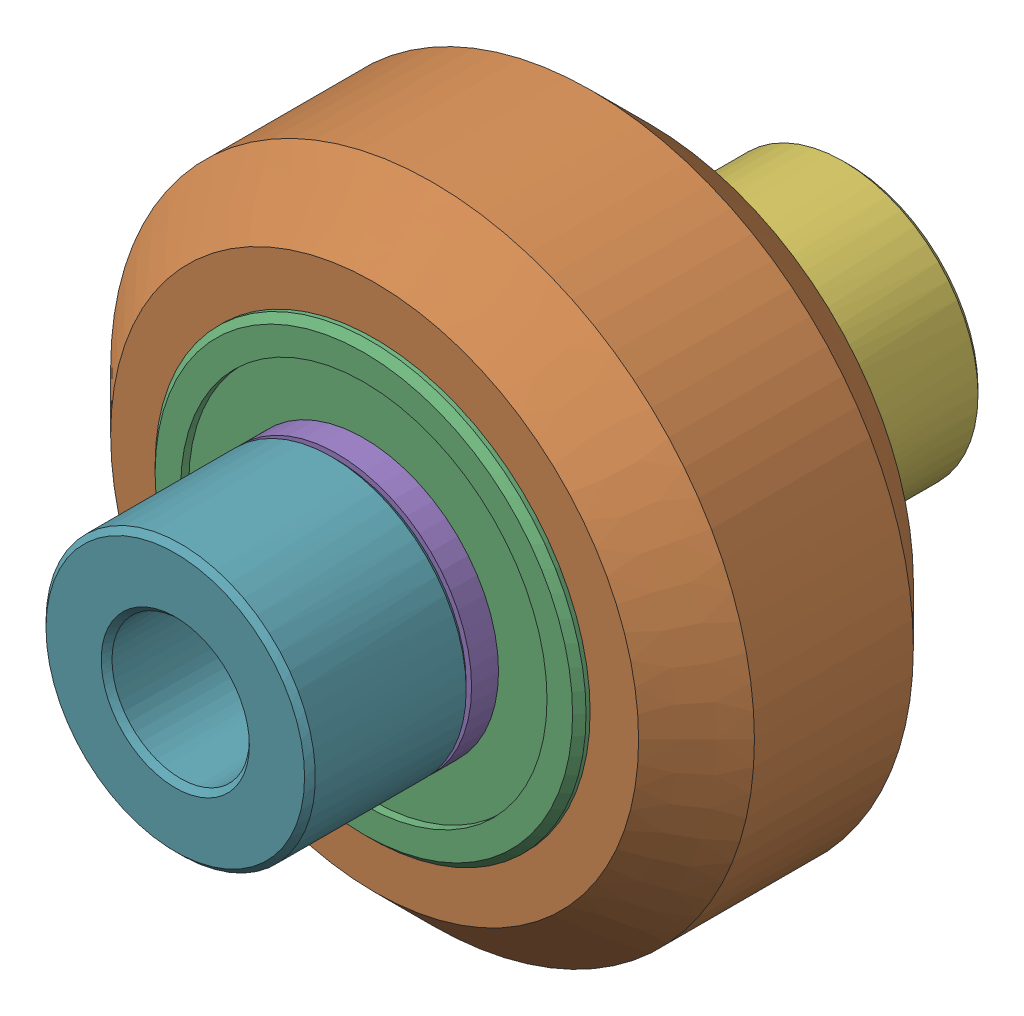
SolidWorks assembly Inboard Wheel Stack_1, configuration Default. Lengths in mm.
Overall size (23.9 23.9 25).
9 component instances, 4 part files, 0 mates.
Components (placement in the parent):
- Xtreme Solid V Wheel Kit Assembly_1-1: Xtreme Solid V Wheel Kit Assembly_1 [Default] at origin size (23.9 23.9 13)
  - Precision Shim - 10x5x1mm-1: Precision Shim - 10x5x1mm [Default] at origin size (10 10 1)
  - Xtreme Solid V Wheel Assembly_1-1: Xtreme Solid V Wheel Assembly_1 [Default] at (45.15 55 -23.5) size (23.9 23.9 11)
    - Xtreme Solid V Wheel-1: Xtreme Solid V Wheel [Default] at (-45.15 -55 30) x (0 0 1) z (-1 0 0) size (10.2 23.9 23.9)
    - Wheel+Kit+-+5x16x5mm+Sealed+Radial+Ball+Bearing.step.f3d-1: Wheel+Kit+-+5x16x5mm+Sealed+Radial+Ball+Bearing.step.f3d [Default] at (-45.15 -55 30) x (0 1 0) z (-1 0 0) size (16 5 16)
    - Wheel+Kit+-+5x16x5mm+Sealed+Radial+Ball+Bearing.step.f3d-2: Wheel+Kit+-+5x16x5mm+Sealed+Radial+Ball+Bearing.step.f3d [Default] at (-45.15 -55 30) x (0 1 0) z (1 0 0) size (16 5 16)
  - Precision Shim - 10x5x1mm-2: Precision Shim - 10x5x1mm [Default] at (0 0 12) size (10 10 1)
- Aluminum Spacer 6mm-1: Aluminum Spacer 6mm [Default] at (0 0 -6) size (10 10 6)
- Aluminum Spacer 6mm-2: Aluminum Spacer 6mm [Default] at (0 0 13) size (10 10 6)
